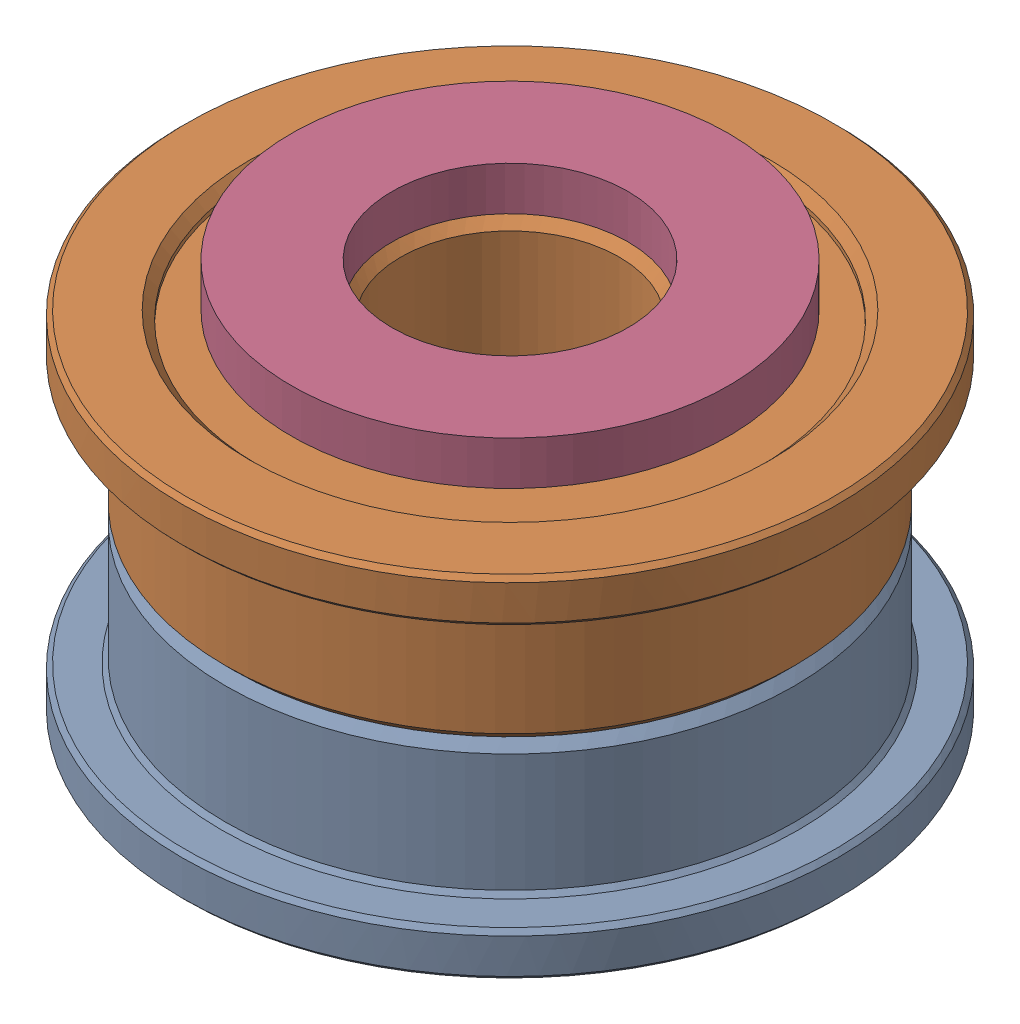
SolidWorks assembly Idler Pulley Assembly v3_3, configuration Default. Lengths in mm.
Overall size (15 10 15).
4 component instances, 3 part files, 0 mates.
Components (placement in the parent):
- F695-2RS v1 (1)-1: F695-2RS v1 (1) [Default] at origin size (15 4 15)
- F695-2RS v1 (2)-1: F695-2RS v1 (2) [Default] at (0 8 0) x (-1 0 0) z (0 0 1) size (15 4 15)
- M5 1mm Spacer-1: M5 1mm Spacer [Default] at (0 0 -350) size (10 1 10)
- M5 1mm Spacer-2: M5 1mm Spacer [Default] at (0 9 -350) size (10 1 10)
